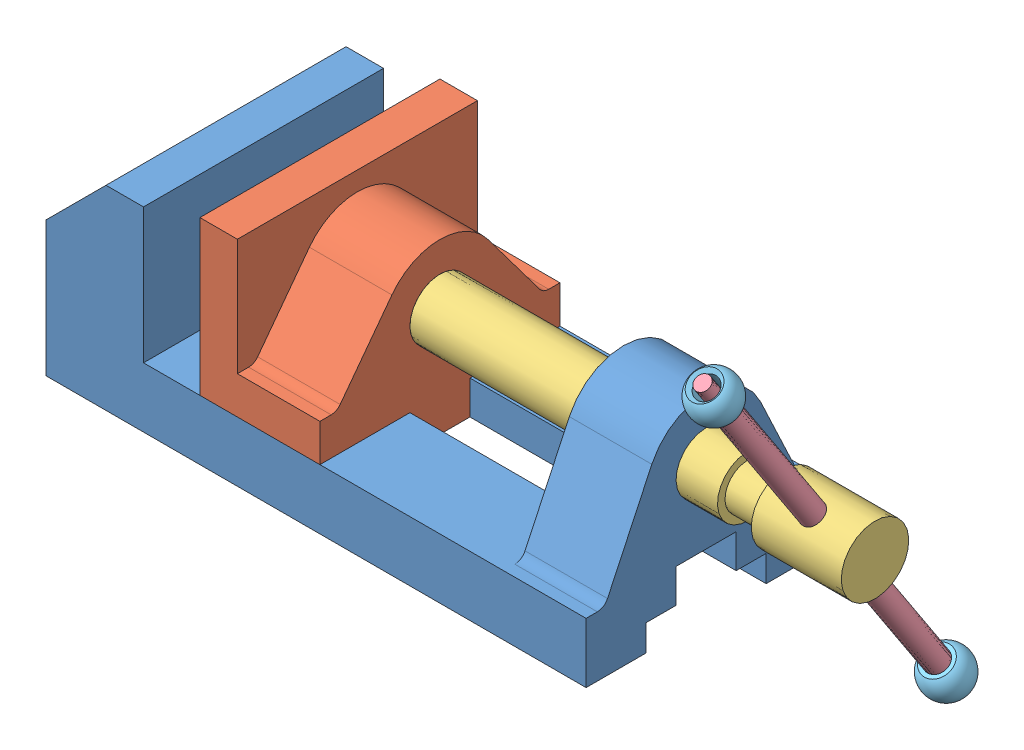
SolidWorks assembly Assem1, configuration Default. Lengths in mm.
Overall size (189.03 109.05 77.58).
6 component instances, 5 part files, 12 mates.
Components (placement in the parent):
- Part1-1: Part1 [Default] at (59.2612 59.2304 106.2094) size (144 52 64)
- Part2-1: Part2 [Default] at (38.2885 85.2304 106.2094) size (32 50.05 64)
- Part3-1: Part3 [Default] at (101.2885 87.2304 106.2094) x (0 0.836334 0.54822) z (-1 0 0) size (18 18 138)
- Part4-1: Part4 [Default] at (164.2885 87.2304 106.2094) x (-0.804254 -0.325799 0.497021) z (0 0.836334 0.54822) size (6 6 124)
- Part7-1: Part7 [Default] at (164.2885 134.4833 137.1839) x (-0.030576 -0.547964 0.835943) z (-0.999532 0.016762 -0.025572) size (12 9 12)
- Part7-2: Part7 [Default] at (164.2885 39.9775 75.235) x (0.994113 0.059398 -0.090615) z (-0.108348 0.544993 -0.831411) size (12 9 12)
Mates (geometry in assembly coordinates):
- Coincident2: coincident: plane of assembly; plane of assembly; plane of Part1-1 through (-12.7398 58.2304 98.2094) normal (0 0 1); plane of Part2-1 through (60.2885 85.2304 98.2094) normal (0 0 -1)
- Coincident3: coincident: plane of assembly; plane of assembly; plane of Part1-1 through (13.2612 67.2304 138.2094) normal (0 1 0); plane of Part2-1 through (60.2885 67.2304 106.2094) normal (0 -1 0)
- Concentric1: concentric: cylinder of assembly; cylinder of assembly; cylinder of Part2-1 through (60.2885 87.2304 106.2094) axis (-1 0 0) radius 8; cylinder of Part3-1 through (51.2885 87.2304 106.2094) axis (1 0 0) radius 6
- Coincident4: coincident: plane of assembly; plane of assembly; plane of Part2-1 through (60.2885 85.2304 106.2094) normal (1 0 0); plane of Part3-1 through (60.2885 87.2304 106.2094) normal (-1 0 0)
- Concentric2: concentric: cylinder of assembly; cylinder of assembly; cylinder of Part3-1 through (164.2885 66.3221 92.5039) axis (0 0.836334 0.54822) radius 3; cylinder of Part4-1 through (164.2885 130.7198 134.7169) axis (0 -0.836334 -0.54822) radius 3
- Distance1: distance = 62 mm: plane of assembly; cylinder of assembly; plane of Part4-1 through (164.2885 139.0831 140.1991) normal (0 0.836334 0.54822); cylinder of Part3-1 through (176.2885 87.2304 106.2094) axis (-1 0 0) radius 9
- Coincident10: coincident: plane of assembly; plane of assembly; plane of Part4-1 through (164.2885 43.741 77.702) normal (0 -0.836334 -0.54822); plane of Part7-2 through (164.2885 43.741 77.702) normal (0 0.836334 0.54822)
- Coincident11: coincident: line of assembly; line of assembly; axis of Part4-1 through (164.2885 35.3777 72.2198) axis (0 0.836334 0.54822); axis of Part7-2 through (164.2885 36.7644 73.1288) axis (0 0.836334 0.54822)
- Coincident13: coincident: plane of assembly; plane of assembly; plane of Part4-1 through (164.2885 43.741 77.702) normal (0 -0.836334 -0.54822); plane of Part7-2 through (164.2885 43.741 77.702) normal (0 0.836334 0.54822)
- Concentric4: concentric: cylinder of assembly; cylinder of assembly; cylinder of Part4-1 through (164.2885 139.0831 140.1991) axis (0 -0.836334 -0.54822) radius 2; cylinder of Part7-1 through (164.2885 127.4569 132.5781) axis (0 -0.836334 -0.54822) radius 2.9686
- Coincident14: coincident: plane of assembly; plane of assembly; plane of Part4-1 through (164.2885 130.7198 134.7169) normal (0 0.836334 0.54822); plane of Part7-1 through (164.2885 130.7198 134.7169) normal (0 -0.836334 -0.54822)
- Distance2: distance = 15.0272 mm: plane of assembly; plane of assembly; plane of Part1-1 through (13.2612 103.2304 138.2094) normal (1 0 0); plane of Part2-1 through (28.2885 85.2304 106.2094) normal (-1 0 0)
